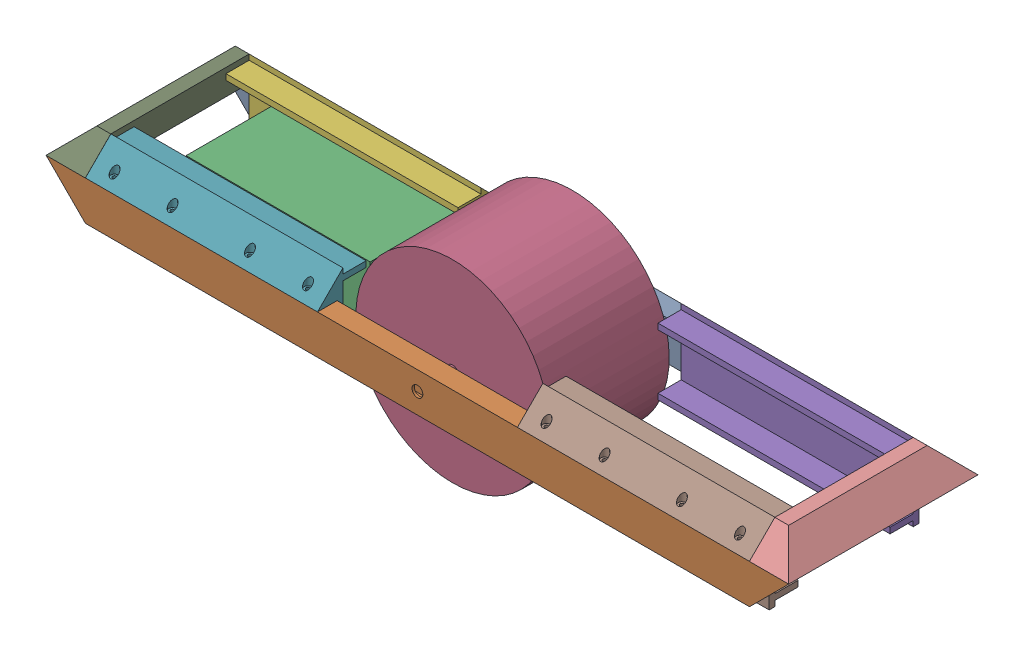
SolidWorks assembly Main Assembly, configuration Default. Lengths in mm.
Overall size (960 273.13 244.7).
10 component instances, 5 part files, 24 mates.
Components (placement in the parent):
- B-D Side Rail-1: B-D Side Rail [Default] at (-459.7418 84.8735 184.9377) size (960 50.8 25.4)
- B-D Side Rail-2: B-D Side Rail [Default] at (-459.7418 84.8735 404.1061) size (960 50.8 25.4)
- Battery-1: Battery [Default] at (-402.2933 83.0735 356.8377) size (238 70 139)
- mock up wheel-1: mock up wheel [Default] at (-30.5418 111.2735 229.1035) x (0.995261 -0.097241 0) z (0 0 1) size (250 250 225)
- plywood attach-1: plywood attach [Default] at (398.6582 135.6735 184.9377) x (0 0 1) z (0 -1 0) size (62.9 300 100)
- plywood attach-2: plywood attach [Default] at (-159.7418 135.6735 184.9377) x (0 0 1) z (0 -1 0) size (62.9 300 100)
- plywood attach-5: plywood attach [Default] at (-459.7418 135.6735 429.5061) x (0 0 -1) z (0 -1 0) size (62.9 300 100)
- plywood attach-6: plywood attach [Default] at (98.6582 135.6735 429.5061) x (0 0 -1) z (0 -1 0) size (62.9 300 100)
- front shield-1: front shield [Default] at (-477.6418 135.6735 184.9377) x (0 -1 0) z (0 0 -1) size (32.9 50.8 244.7)
- front shield-2: front shield [Default] at (416.5582 135.6735 429.6377) x (0 -1 0) z (0 0 1) size (32.9 50.8 244.7)
Mates (geometry in assembly coordinates):
- Parallel1: parallel anti-aligned: plane of B-D Side Rail-1 through (-459.7418 84.8735 210.3377) normal (0 0 1); plane of B-D Side Rail-2 through (-459.7418 84.8735 404.1061) normal (0 0 -1)
- Parallel2: parallel aligned: plane of B-D Side Rail-1 through (-510.5418 135.6735 210.3377) normal (0 1 0); plane of B-D Side Rail-2 through (-510.5418 135.6735 429.5061) normal (0 1 0)
- Concentric1: concentric aligned: cylinder of B-D Side Rail-1 through (-30.5418 111.2735 210.3377) axis (0 0 -1) radius 7; cylinder of B-D Side Rail-2 through (-30.5418 111.2735 429.5061) axis (0 0 -1) radius 7
- Concentric2: concentric aligned: cylinder of B-D Side Rail-2 through (-30.5418 111.2735 429.5061) axis (0 0 -1) radius 7; cylinder of mock up wheel-1 through (-30.5418 111.2735 419.1035) axis (0 0 -1) radius 7
- Concentric3: concentric anti-aligned: cylinder of B-D Side Rail-1 through (-30.5418 111.2735 210.3377) axis (0 0 -1) radius 7; cylinder of mock up wheel-1 through (-30.5418 111.2735 194.1035) axis (0 0 1) radius 7
- Coincident3: coincident anti-aligned: plane of B-D Side Rail-1 through (-510.5418 135.6735 210.3377) normal (0 1 0); plane of plywood attach-1 through (98.6582 135.6735 184.9377) normal (0 -1 0)
- Coincident4: coincident anti-aligned: plane of B-D Side Rail-1 through (-459.7418 84.8735 210.3377) normal (0 0 1); plane of plywood attach-1 through (98.6582 84.8735 210.3377) normal (0 0 -1)
- Coincident5: coincident anti-aligned: plane of B-D Side Rail-1 through (-510.5418 135.6735 210.3377) normal (0 1 0); plane of plywood attach-2 through (-459.7418 135.6735 184.9377) normal (0 -1 0)
- Coincident6: coincident anti-aligned: plane of B-D Side Rail-1 through (-459.7418 84.8735 210.3377) normal (0 0 1); plane of plywood attach-2 through (-459.7418 84.8735 210.3377) normal (0 0 -1)
- Coincident9: coincident: line of B-D Side Rail-1 through (-459.7418 84.8735 210.3377) axis (0 0 -1); plane of plywood attach-2 through (-459.7418 135.6735 184.9377) normal (-1 0 0)
- Coincident10: coincident: line of B-D Side Rail-1 through (398.6582 84.8735 210.3377) axis (0 0 -1); plane of plywood attach-1 through (398.6582 135.6735 184.9377) normal (1 0 0)
- Coincident17: coincident anti-aligned: plane of B-D Side Rail-2 through (-459.7418 84.8735 404.1061) normal (0 0 -1); plane of plywood attach-5 through (-159.7418 84.8735 404.1061) normal (0 0 1)
- Coincident18: coincident anti-aligned: plane of B-D Side Rail-2 through (-510.5418 135.6735 429.5061) normal (0 1 0); plane of plywood attach-5 through (-159.7418 135.6735 429.5061) normal (0 -1 0)
- Coincident19: coincident: line of B-D Side Rail-2 through (-459.7418 84.8735 429.5061) axis (0 0 -1); plane of plywood attach-5 through (-459.7418 135.6735 429.5061) normal (-1 0 0)
- Coincident20: coincident anti-aligned: plane of B-D Side Rail-2 through (-459.7418 84.8735 404.1061) normal (0 0 -1); plane of plywood attach-6 through (398.6582 84.8735 404.1061) normal (0 0 1)
- Coincident21: coincident anti-aligned: plane of B-D Side Rail-2 through (-510.5418 135.6735 429.5061) normal (0 1 0); plane of plywood attach-6 through (398.6582 135.6735 429.5061) normal (0 -1 0)
- Coincident22: coincident: line of B-D Side Rail-2 through (398.6582 84.8735 429.5061) axis (0 0 -1); plane of plywood attach-6 through (398.6582 135.6735 429.5061) normal (1 0 0)
- Coincident23: coincident anti-aligned: plane of Battery-1 through (-402.2933 153.0735 217.8377) normal (0 0 -1); plane of plywood attach-2 through (-459.7418 154.0735 217.8377) normal (0 0 1)
- Coincident24: coincident anti-aligned: plane of Battery-1 through (-402.2933 83.0735 356.8377) normal (0 -1 0); plane of plywood attach-2 through (-459.7418 83.0735 217.8377) normal (0 1 0)
- Coincident25: coincident anti-aligned: plane of B-D Side Rail-1 through (-510.5418 135.6735 210.3377) normal (0 1 0); plane of front shield-1 through (-510.5418 135.6735 184.9377) normal (0 -1 0)
- Coincident26: coincident anti-aligned: line of B-D Side Rail-1 through (-510.5418 135.6735 210.3377) axis (0 0 -1); line of front shield-1 through (-510.5418 135.6735 184.9377) axis (0 0 1)
- Coincident27: coincident anti-aligned: line of B-D Side Rail-1 through (449.4582 135.6735 184.9377) axis (-1 0 0); line of front shield-1 through (-510.5418 135.6735 184.9377) axis (1 0 0)
- Coincident28: coincident anti-aligned: plane of B-D Side Rail-1 through (-510.5418 135.6735 210.3377) normal (0 1 0); plane of front shield-2 through (449.4582 135.6735 429.6377) normal (0 -1 0)
- Coincident29: coincident aligned: line of plywood attach-1 through (398.6582 168.5735 217.8377) axis (0 -0.707107 -0.707107); line of front shield-2 through (398.6582 168.5752 217.8394) axis (0 -0.707107 -0.707107)
